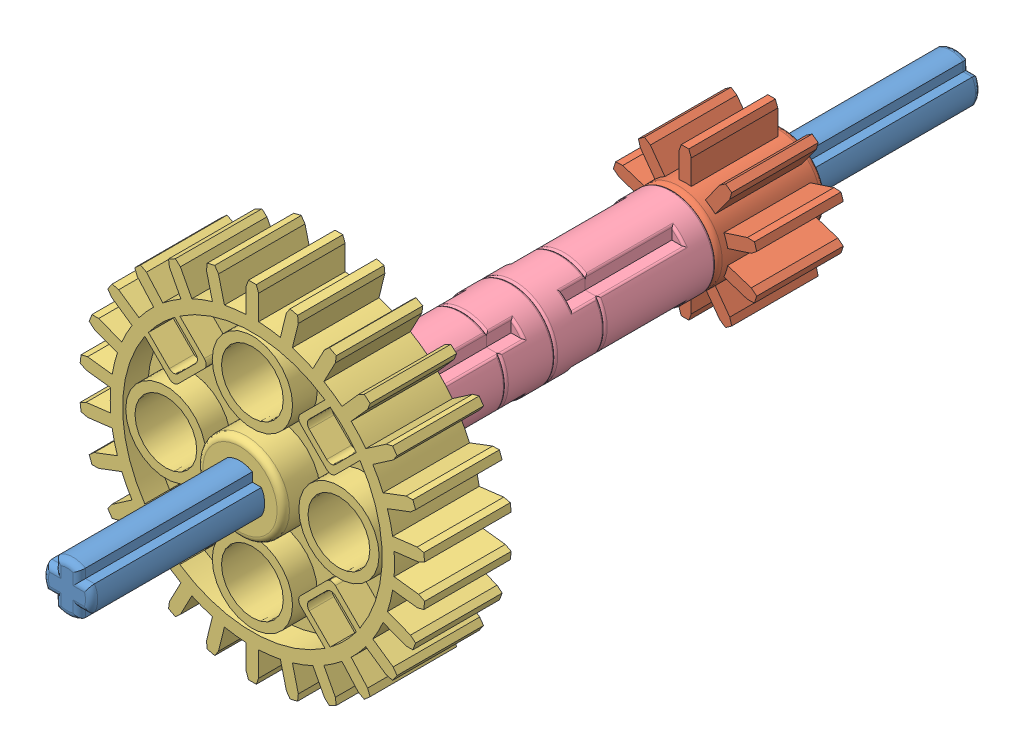
SolidWorks assembly Subconjunto 1º aumento, configuration Default. Lengths in mm.
Overall size (27.87 28 72).
7 component instances, 4 part files, 13 mates.
Components (placement in the parent):
- Veio-1: Veio [Veio Direção] at (-1.1123 2.8833 -19.3719) size (4 4 72)
- Roda Dentada 10-1: Roda Dentada 10 [Default] at (-1.1123 2.8833 -0.8719) size (11.6 12 9)
- Roda Dentada 26-2: Roda Dentada 26 [Default] at (-1.1123 2.8833 34.1281) size (27.87 28 9)
- Freio-1: Freio [Freio Pequeno] at (-1.1123 2.8833 12.6281) size (7 7 4.02)
- Freio-2: Freio [Freio Pequeno] at (-1.1123 2.8833 20.6281) x (1 0 0) z (0 0 -1) size (7 7 4.02)
- Freio-3: Freio [Frei Grande] at (-1.1123 2.8833 20.6281) size (7 7 9.02)
- Freio-4: Freio [Frei Grande] at (-1.1123 2.8833 12.6281) x (-1 0 0) z (0 0 -1) size (7 7 9.02)
Mates (geometry in assembly coordinates):
- Concentric11: concentric aligned: cylinder of Veio-1 through (-1.1123 2.8833 52.6281) axis (0 0 -1) radius 2; cylinder of Roda Dentada 10-1 through (-1.1123 2.8833 3.6281) axis (0 0 -1) radius 2
- Concentric21: concentric aligned: cylinder of Veio-1 through (-1.1123 2.8833 52.6281) axis (0 0 -1) radius 2; cylinder of Roda Dentada 26-2 through (-1.1123 2.8833 37.6281) axis (0 0 -1) radius 2
- Concentric31: concentric aligned: cylinder of Veio-1 through (-1.1123 2.8833 52.6281) axis (0 0 -1) radius 2; cylinder of Freio-1 through (-1.1123 2.8833 16.6281) axis (0 0 -1) radius 2
- Concentric41: concentric anti-aligned: cylinder of Veio-1 through (-1.1123 2.8833 52.6281) axis (0 0 -1) radius 2; cylinder of Freio-2 through (-1.1123 2.8833 16.6281) axis (0 0 1) radius 2
- Concentric51: concentric aligned: cylinder of Veio-1 through (-1.1123 2.8833 52.6281) axis (0 0 -1) radius 2; cylinder of Freio-3 through (-1.1123 2.8833 29.6281) axis (0 0 -1) radius 2
- Concentric61: concentric anti-aligned: cylinder of Veio-1 through (-1.1123 2.8833 52.6281) axis (0 0 -1) radius 2; cylinder of Freio-4 through (-1.1123 2.8833 3.6281) axis (0 0 1) radius 2
- Coincident2: coincident anti-aligned: plane of Veio-1 through (-0.1123 3.8833 52.6281) normal (0 1 0); plane of Freio-2 through (-0.1123 3.8833 16.6281) normal (0 -1 0)
- Coincident3: coincident anti-aligned: plane of Roda Dentada 10-1 through (-1.1123 2.8833 3.6281) normal (0 0 1); plane of Freio-4 through (-1.1123 2.8833 3.6281) normal (0 0 -1)
- Coincident5: coincident anti-aligned: plane of Freio-1 through (-1.1123 2.8833 12.6281) normal (0 0 -1); plane of Freio-4 through (-1.1123 2.8833 12.6281) normal (0 0 1)
- Coincident6: coincident anti-aligned: plane of Freio-1 through (-1.1123 2.8833 16.6281) normal (0 0 1); plane of Freio-2 through (-1.1123 2.8833 16.6281) normal (0 0 -1)
- Coincident7: coincident anti-aligned: plane of Freio-2 through (-1.1123 2.8833 20.6281) normal (0 0 1); plane of Freio-3 through (-1.1123 2.8833 20.6281) normal (0 0 -1)
- Coincident8: coincident anti-aligned: plane of Roda Dentada 26-2 through (-1.1123 2.8833 29.6281) normal (0 0 -1); plane of Freio-3 through (-1.1123 2.8833 29.6281) normal (0 0 1)
- Width1: width aligned: plane of Veio-1 through (-1.1123 2.8833 -19.3719) normal (0 0 -1); plane of Roda Dentada 10-1 through (-1.1123 2.8833 52.6281) normal (0 0 1); plane of Veio-1 through (-1.1123 2.8833 -5.3719) normal (0 0 -1); plane of Roda Dentada 26-2 through (-1.1123 2.8833 38.6281) normal (0 0 1)
